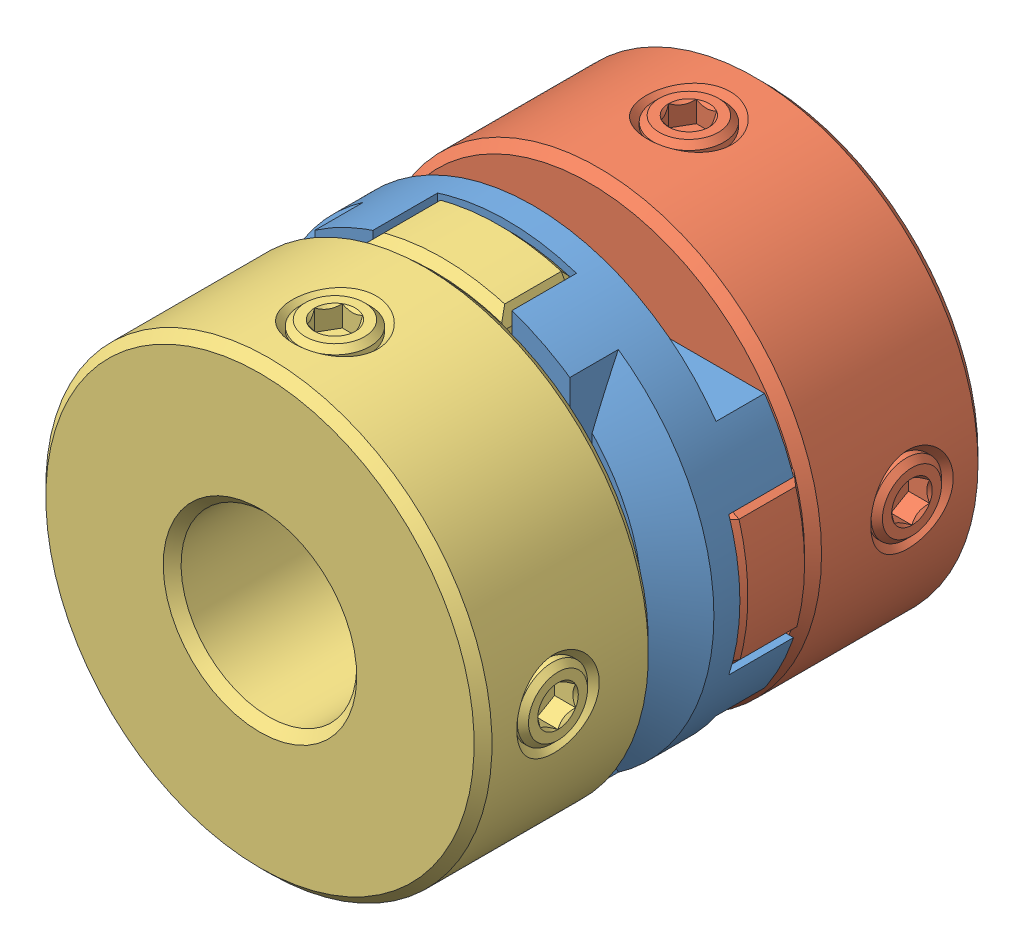
SolidWorks assembly Assem1, configuration Default. Lengths in mm.
Overall size (25.52 25.52 28.68).
3 component instances, 3 part files, 4 mates.
Components (placement in the parent):
- CouplingCenter_59985K630-1: CouplingCenter_59985K630 [59985K63] at (7.6605 14.6137 19.5344) size (25.4 25.4 7.92)
- halfInCoupling_59985K190-1: halfInCoupling_59985K190 [59985K19] at (7.6605 14.6137 19.4804) size (25.52 25.52 14.06)
- 10mmCoupling_59985K305-1: 10mmCoupling_59985K305 [59985K305] at (7.6605 14.6137 19.5884) x (0 1 0) z (0 0 -1) size (25.52 25.52 14.06)
Mates (geometry in assembly coordinates):
- Concentric1: concentric anti-aligned: cylinder of CouplingCenter_59985K630-1 through (7.6605 14.6137 15.572) axis (0 0 1) radius 12.7; cylinder of halfInCoupling_59985K190-1 through (7.6605 14.6137 19.255) axis (0 0 -1) radius 12.7
- Coincident4: coincident anti-aligned: plane of CouplingCenter_59985K630-1 through (20.3605 10.6577 19.255) normal (0 0 -1); plane of halfInCoupling_59985K190-1 through (7.6605 14.6137 19.255) normal (0 0 1)
- Coincident6: coincident anti-aligned: plane of CouplingCenter_59985K630-1 through (3.7044 1.9137 19.8138) normal (0 0 1); plane of 10mmCoupling_59985K305-1 through (7.6605 14.6137 19.8138) normal (0 0 -1)
- Distance1: distance = 0 mm: cylinder of 10mmCoupling_59985K305-1 through (7.6605 14.6137 19.8138) axis (0 0 1) radius 12.7; cylinder of CouplingCenter_59985K630-1 through (7.6605 14.6137 15.572) axis (0 0 1) radius 12.7
